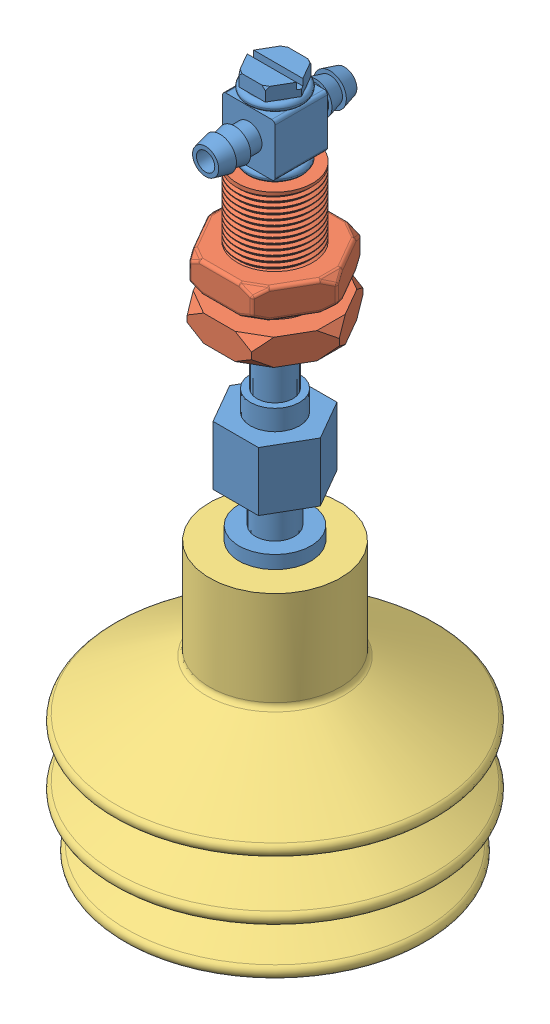
SolidWorks assembly 三通继手, configuration 默认. Lengths in mm.
Overall size (51.52 104.71 51.52).
3 component instances, 3 part files, 4 mates.
Components (placement in the parent):
- 三通继手1-1: 三通继手1 [默认] at origin size (13.86 62.71 21.2)
- 继手2-1: 继手2 [默认] at (0 29.1 0) size (19.63 21.32 17)
- MP50吸盘-1: MP50吸盘 [默认] at (0 -15 0) x (0.999013 0 0.044422) z (-0.044422 0 0.999013) size (49.38 42 49.38)
Mates (geometry in assembly coordinates):
- 同心1: concentric anti-aligned: circle of 三通继手1-1; circle of 继手2-1
- 重合2: coincident anti-aligned: plane of 三通继手1-1 through (0 50.1 0) normal (0 -1 0); plane of 继手2-1 through (0 50.1 0) normal (0 1 0)
- 同心2: concentric aligned: circle of 三通继手1-1; circle of MP50吸盘-1
- 重合3: coincident anti-aligned: plane of 三通继手1-1 through (0 0 0) normal (0 -1 0); plane of MP50吸盘-1 through (0 0 0) normal (0 1 0)
